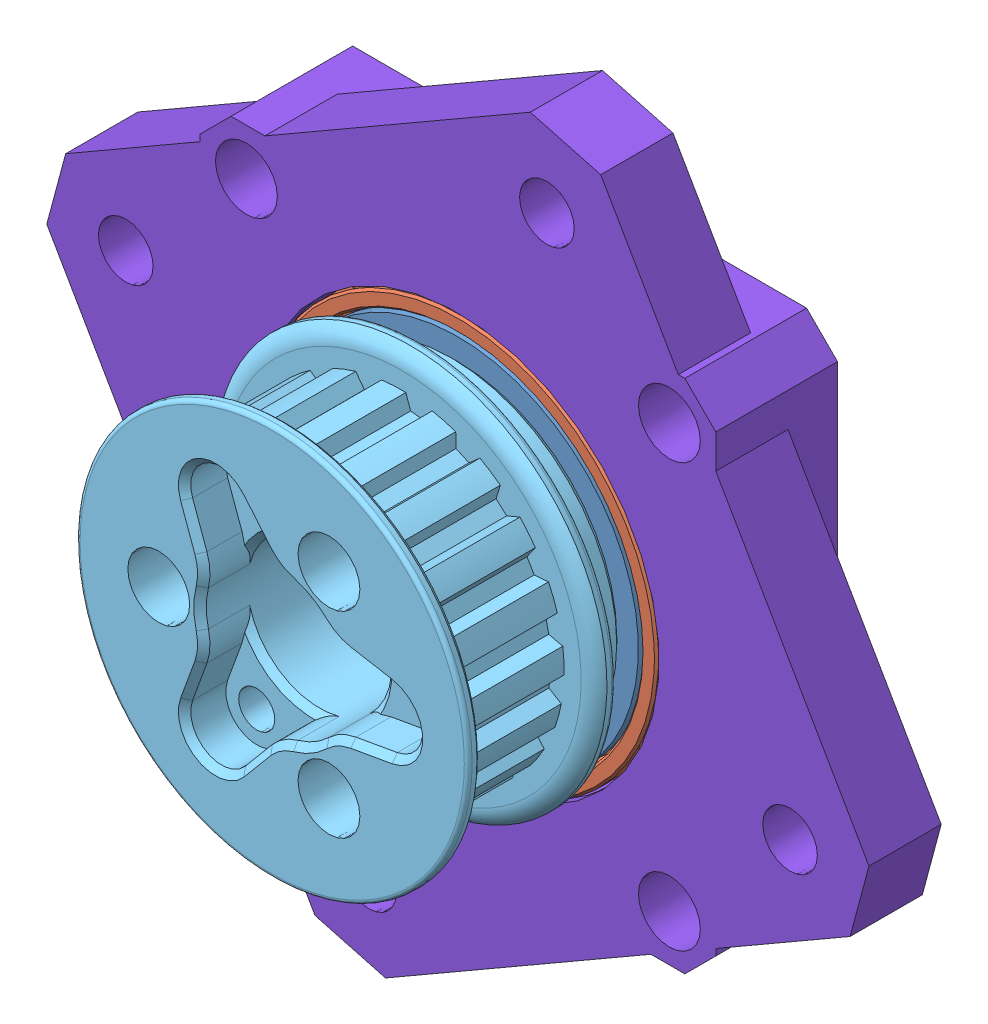
SolidWorks assembly Cycloidal Drive, configuration Default. Lengths in mm.
Overall size (85.38 85.38 43.89).
11 component instances, 10 part files, 0 mates.
Components (placement in the parent):
- Part 4-1: Part 4 [Default] at (1.0989 0.2528 -5.1064) size (35 35 5.4)
- Part 7-1: Part 7 [Default] at (1.0989 0.2528 -5.1064) size (41.2 41.39 5.79)
- Part 3-1: Part 3 [Default] at (1.0989 0.2528 -5.1064) size (13 13 11.8)
- Part 2-1: Part 2 [Default] at (1.0989 0.2528 -5.1064) size (16.5 17.75 5.43)
- Stepper v6-1: Stepper v6 [Default] at (0.0989 0.2528 27.8936) x (0.5 -0.866025 0) z (0 0 1) size (38 38 18)
- amt102-v _1_-1: amt102-v _1_ [Default] at origin size (85.38 85.38 9.09)
  - amt102-v_01-1: amt102-v_01 [Default] at (0.0989 0.2528 32.9636) x (0.866025 0.5 0) z (0 0 1) size (62.5 62.5 9.09) (hidden)
  - amt102-v_06-1: amt102-v_06 [Default] at (0.0989 0.2528 32.9636) x (0.866025 0.5 0) z (0 0 1) size (11.92 11.92 7.8) (hidden)
- Part 6-1: Part 6 [Default] at (1.0989 0.2528 -5.1064) size (13.84 15.43 5.64)
- Part 1-1: Part 1 [Default] at (1.0989 0.2528 -5.1064) size (38.57 38.73 5.4)
- Part 5-1: Part 5 [Default] at (1.0989 0.2528 -5.1064) size (79.7 79.7 11.8)
